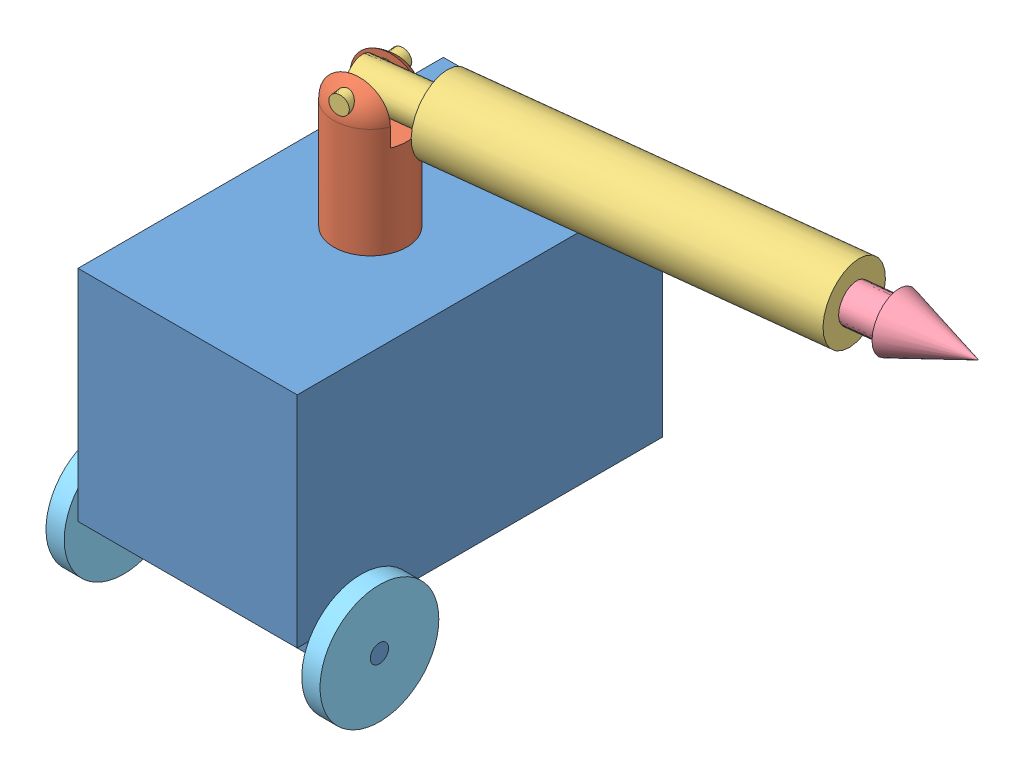
SolidWorks assembly gobotgo, configuration Default. Lengths in mm.
Overall size (469.82 331.73 269.81).
6 component instances, 5 part files, 10 mates.
Components (placement in the parent):
- cart_body-1: cart_body [Default] at origin size (190.5 228.6 254)
- arm_base_link-1: arm_base_link [Default] at (0 127 0) x (-0.13667 0 -0.990617) z (0.990617 0 -0.13667) size (50.8 98.2 50.8)
- arm_link2-1: arm_link2 [Default] at (169.8058 159.8986 -23.4272) x (0.99041 -0.020413 -0.136641) z (0.13667 0 0.990617) size (304.8 50.8 50.8)
- arm_spear-1: arm_spear [Default] at (194.9623 159.3801 -26.8979) x (0.99041 -0.020413 -0.136641) z (0.060027 0.954376 0.292512) size (304.8 38.1 38.1)
- wheel-1: wheel [Default] at (88.9 -88.9 88.9) x (0 0 1) z (-1 0 0) size (82.55 82.55 12.7)
- wheel-2: wheel [Default] at (-88.9 -88.9 88.9) x (0 -0.924225 -0.381849) z (1 0 0) size (82.55 82.55 12.7)
Mates (geometry in assembly coordinates):
- Coincident1: coincident anti-aligned: plane of cart_body-1 through (-76.2 76.2 127) normal (0 1 0); plane of arm_base_link-1 through (-3.4714 76.2 -25.1617) normal (0 -1 0)
- Concentric1: concentric aligned: cylinder of cart_body-1 through (0 101.6 0) axis (0 -1 0) radius 6.35; cylinder of arm_base_link-1 through (0 101.6 0) axis (0 -1 0) radius 6.35
- Tangent1: tangent anti-aligned: plane of arm_base_link-1 through (-98.9109 177.8 26.4665) normal (-0.13667 0 -0.990617); cylinder of arm_link2-1 through (-6.2891 163.5281 0.8677) axis (0.99041 -0.020413 -0.136641) radius 12.7
- Concentric2: concentric aligned: cylinder of arm_base_link-1 through (15.6214 163.3985 113.2275) axis (-0.13667 0 -0.990617) radius 6.35; cylinder of arm_link2-1 through (3.4714 163.3985 25.1617) axis (-0.13667 0 -0.990617) radius 6.35
- Concentric3: concentric anti-aligned: cylinder of arm_link2-1 through (69.1802 161.9726 -9.5444) axis (0.99041 -0.020413 -0.136641) radius 12.7; cylinder of arm_spear-1 through (320.7443 156.7876 -44.2513) axis (-0.99041 0.020413 0.136641) radius 12.7
- LimitDistance1: limit distance = 0 mm anti-aligned: plane of arm_spear-1 through (69.1802 161.9726 -9.5444) normal (-0.99041 0.020413 0.136641); plane of arm_link2-1 through (69.1802 161.9726 -9.5444) normal (0.99041 -0.020413 -0.136641)
- Concentric4: concentric anti-aligned: cylinder of cart_body-1 through (95.25 -88.9 88.9) axis (-1 0 0) radius 6.35; cylinder of wheel-1 through (82.55 -88.9 88.9) axis (1 0 0) radius 6.35
- Coincident2: coincident aligned: plane of cart_body-1 through (95.25 -88.9 88.9) normal (1 0 0); plane of wheel-1 through (95.25 -88.9 88.9) normal (1 0 0)
- Concentric5: concentric anti-aligned: cylinder of cart_body-1 through (-95.25 -88.9 88.9) axis (1 0 0) radius 6.35; cylinder of wheel-2 through (-82.55 -88.9 88.9) axis (-1 0 0) radius 6.35
- Coincident3: coincident aligned: plane of cart_body-1 through (-95.25 -88.9 88.9) normal (-1 0 0); plane of wheel-2 through (-95.25 -88.9 88.9) normal (-1 0 0)
